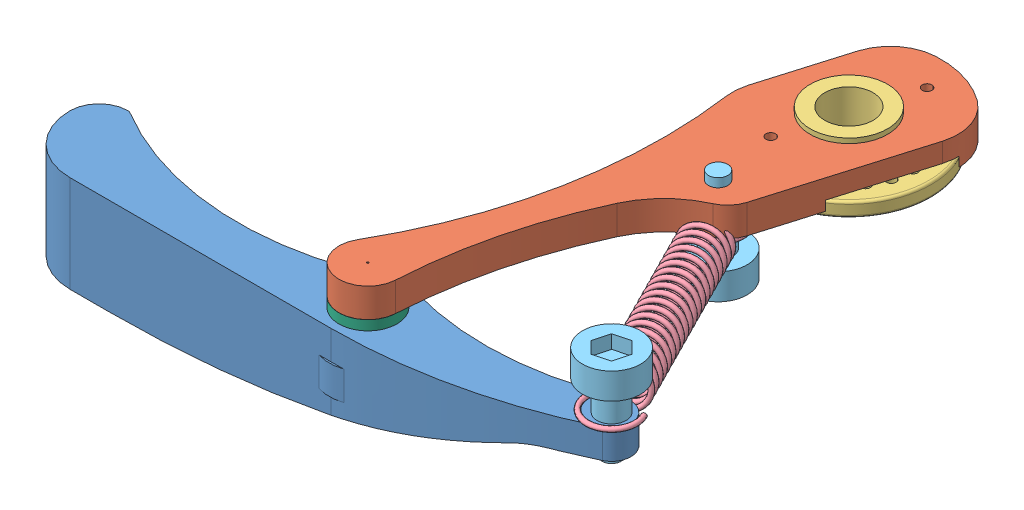
SolidWorks assembly AssemblyLeg_v2_right, configuration Default. Lengths in mm.
Overall size (59.24 15.8 54.03).
7 component instances, 6 part files, 13 mates.
Components (placement in the parent):
- LowerLeg_v2_right-1: LowerLeg_v2_right [Standard] at (-46.982 -8.259 12.3103) size (57 10 9.24)
- UpperLeg_v2_right-1: UpperLeg_v2_right [Standard] at (-2.5862 4.741 -29.832) x (-0.284896 0 0.958558) z (0 -1 0) size (52.5 13 3)
- HS-81MG_horn-1: HS-81MG_horn [Default] at (-2.5862 -1.759 -29.832) x (-0.284896 0 0.958558) z (0 1 0) size (17 17 5)
- spring-2: spring [Default] at (-2.1428 -2.0089 -14.7648) x (0 1 0) z (0.451588 0 0.892227) size (5 5.5 30.5)
- Schraube-2: Schraube [Standard] at (-3.2717 -4.359 -16.9953) x (0 1 0) z (-0.11305 0 0.993589) size (9.7 6 6)
- Schraube-3: Schraube [Standard] at (8.018 0.841 5.3103) x (0 -1 0) z (-0.709749 0 0.704455) size (9.7 6 6)
- spacerM3_1mm-1: spacerM3_1mm [Default] at (-13.982 -2.259 8.5103) x (1 0 0) z (0 1 0) size (6 6 1)
Mates (geometry in assembly coordinates):
- Concentric1: concentric aligned: cylinder of UpperLeg_v2_right-1 through (-2.5862 1.741 -29.832) axis (0 -1 0) radius 4; cylinder of HS-81MG_horn-1 through (-2.5862 2.241 -29.832) axis (0 -1 0) radius 4
- Concentric2: concentric aligned: cylinder of UpperLeg_v2_right-1 through (-0.7344 -1.259 -36.0626) axis (0 -1 0) radius 0.5; cylinder of HS-81MG_horn-1 through (-0.7344 -1.259 -36.0626) axis (0 -1 0) radius 0.5
- Coincident1: coincident anti-aligned: plane of UpperLeg_v2_right-1 through (-2.5862 -0.259 -29.832) normal (0 -1 0); plane of HS-81MG_horn-1 through (-2.5862 -0.259 -29.832) normal (0 1 0)
- Concentric6: concentric aligned: cylinder of LowerLeg_v2_right-1 through (-13.982 3.741 8.5103) axis (0 -1 0) radius 0.65; cylinder of spacerM3_1mm-1 through (-13.982 -1.259 8.5103) axis (0 -1 0) radius 1.5
- Coincident5: coincident anti-aligned: plane of LowerLeg_v2_right-1 through (-16.982 -2.259 7.8103) normal (0 1 0); plane of spacerM3_1mm-1 through (-13.982 -2.259 8.5103) normal (0 -1 0)
- Coincident6: coincident anti-aligned: plane of UpperLeg_v2_right-1 through (16.0656 -1.259 -39.9369) normal (0 -1 0); plane of spacerM3_1mm-1 through (-13.982 -1.259 8.5103) normal (0 1 0)
- Concentric7: concentric aligned: cylinder of LowerLeg_v2_right-1 through (-13.982 3.741 8.5103) axis (0 -1 0) radius 0.65; cylinder of UpperLeg_v2_right-1 through (-13.982 1.741 8.5103) axis (0 -1 0) radius 0.1
- Concentric8: concentric aligned: cylinder of UpperLeg_v2_right-1 through (-3.2717 -1.259 -16.9953) axis (0 -1 0) radius 1; cylinder of Schraube-2 through (-3.2717 -4.359 -16.9953) axis (0 -1 0) radius 1
- Coincident7: coincident anti-aligned: plane of UpperLeg_v2_right-1 through (16.0656 -1.259 -39.9369) normal (0 -1 0); plane of Schraube-2 through (-4.7621 -1.259 -17.1649) normal (0 1 0)
- Concentric9: concentric anti-aligned: cylinder of LowerLeg_v2_right-1 through (8.018 3.741 5.3103) axis (0 -1 0) radius 1; cylinder of Schraube-3 through (8.018 0.841 5.3103) axis (0 1 0) radius 1
- Coincident8: coincident anti-aligned: plane of LowerLeg_v2_right-1 through (-16.982 -2.259 7.8103) normal (0 1 0); plane of Schraube-3 through (9.0746 -2.259 6.375) normal (0 -1 0)
- Concentric10: concentric anti-aligned: circle of spring-2; cylinder of Schraube-2 through (-3.2717 -5.1166 -16.9953) axis (0 -1 0) radius 1.5
- Concentric11: concentric aligned: circle of spring-2; cylinder of Schraube-3 through (8.018 1.5987 5.3103) axis (0 1 0) radius 1.5
